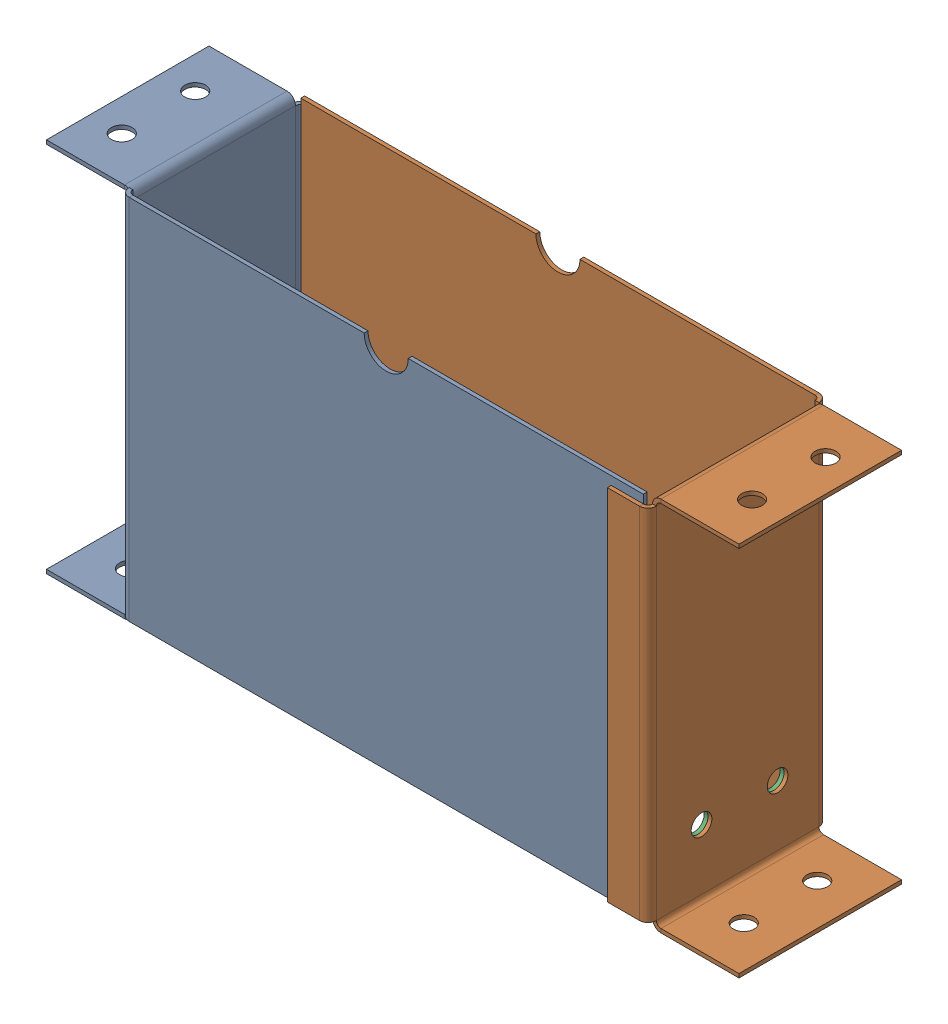
SolidWorks assembly Lower Crushing Chamber Assembly, configuration Default. Lengths in mm.
Overall size (481.56 259.83 126.72).
3 component instances, 3 part files, 8 mates.
Components (placement in the parent):
- Outer Casing - Lower Side 1-1: Outer Casing - Lower Side 1 [Default] at (19.4485 98.189 475.1792) size (418.58 259.83 124.06)
- Outer Casing - Lower Side 2-1: Outer Casing - Lower Side 2 [Default] at (375.0485 98.189 353.7774) x (-1 0 0) z (0 0 -1) size (418.58 259.83 124.06)
- Mesh-1: Mesh [Default] at (16.2735 174.389 472.5224) size (361.95 53.46 116.09)
Mates (geometry in assembly coordinates):
- Parallel1: parallel anti-aligned: plane of Bottom Assembly - Casing Side 1.2-1 through (197.2485 352.189 472.5224) normal (0 0 -1); plane of Bottom Assembly - Casing Side 2.2-1 through (197.2485 352.189 356.4342) normal (0 0 1)
- Parallel2: parallel anti-aligned: line of Bottom Assembly - Casing Side 1.2-1 through (182.0085 352.189 472.5224) axis (-1 0 0); line of Bottom Assembly - Casing Side 2.2-1 through (212.4885 352.189 353.7774) axis (1 0 0)
- Coincident3: coincident anti-aligned: plane of Bottom Assembly - Casing Side 1.2-1 through (19.4485 98.189 353.7774) normal (0 0 1); plane of Bottom Assembly - Casing Side 2.2-1 through (197.2485 352.189 353.7774) normal (0 0 -1)
- Coincident4: coincident aligned: line of Bottom Assembly - Casing Side 1.2-1 through (375.0485 98.189 475.1792) axis (0 1 0); line of Bottom Assembly - Casing Side 2.2-1 through (375.0485 98.189 475.1792) axis (0 1 0)
- Coincident5: coincident aligned: line of Bottom Assembly - Casing Side 1.2-1 through (375.0485 98.189 472.5224) axis (0 0 1); line of Bottom Assembly - Casing Side 2.2-1 through (375.0485 98.189 475.1792) axis (0 0 1)
- Coincident6: coincident anti-aligned: plane of Bottom Assembly - Casing Side 2.2-1 through (378.2235 98.189 353.7774) normal (-1 0 0); plane of Bottom Assembly - Mesh with Screw Holes-1 through (378.2235 174.389 472.5224) normal (1 0 0)
- Coincident7: coincident anti-aligned: line of Bottom Assembly - Casing Side 1.2-1 through (375.0485 174.389 472.5224) axis (-1 0 0); line of Bottom Assembly - Mesh with Screw Holes-1 through (22.1054 174.389 472.5224) axis (1 0 0)
- Parallel3: parallel anti-aligned: plane of Bottom Assembly - Casing Side 2.2-1 through (197.2485 352.189 356.4342) normal (0 0 1); plane of Bottom Assembly - Mesh with Screw Holes-1 through (16.2735 171.7321 356.4342) normal (0 0 -1)
